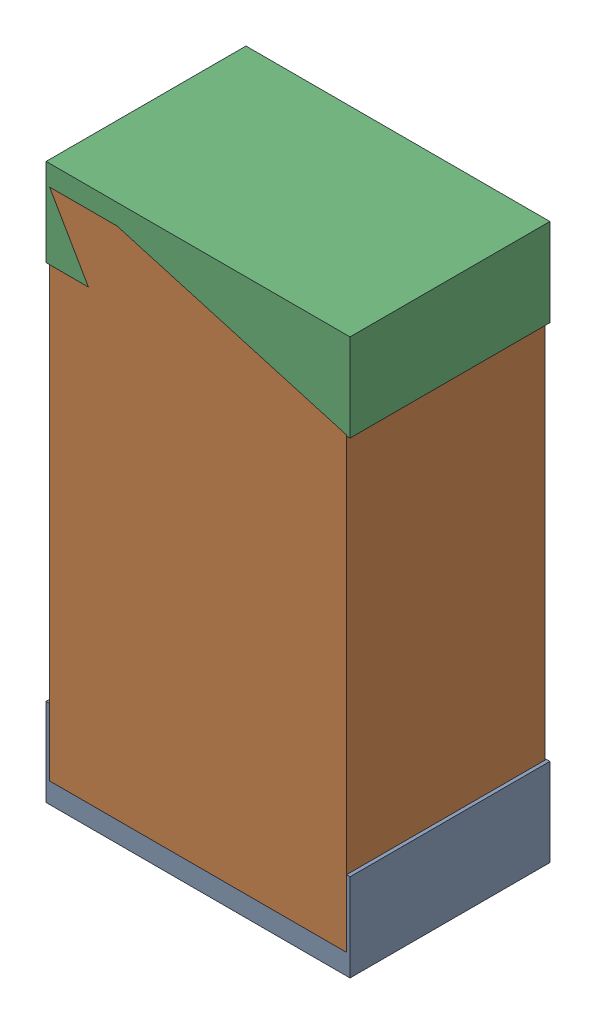
SolidWorks assembly FB1, configuration Default. Lengths in mm.
Overall size (1.3 2.38 0.85).
6 component instances, 2 part files, 0 mates.
Components (placement in the parent):
- 402662288-1: 402662288 [Default] at (148.844 101.616 -1.9574) size (1.3 0.38 0.85)
  - Extruded_16-1: Extruded_16 [Default] at origin size (1.3 0.38 0.85)
- 402662416-1: 402662416 [Default] at (148.844 102.616 -1.9524) size (1.27 2.2 0.85)
  - Extruded_17-1: Extruded_17 [Default] at origin size (1.27 2.2 0.85)
- 402662288-2: 402662288 [Default] at (148.844 103.616 -1.9574) size (1.3 0.38 0.85)
  - Extruded_16-1: Extruded_16 [Default] at origin size (1.3 0.38 0.85)
